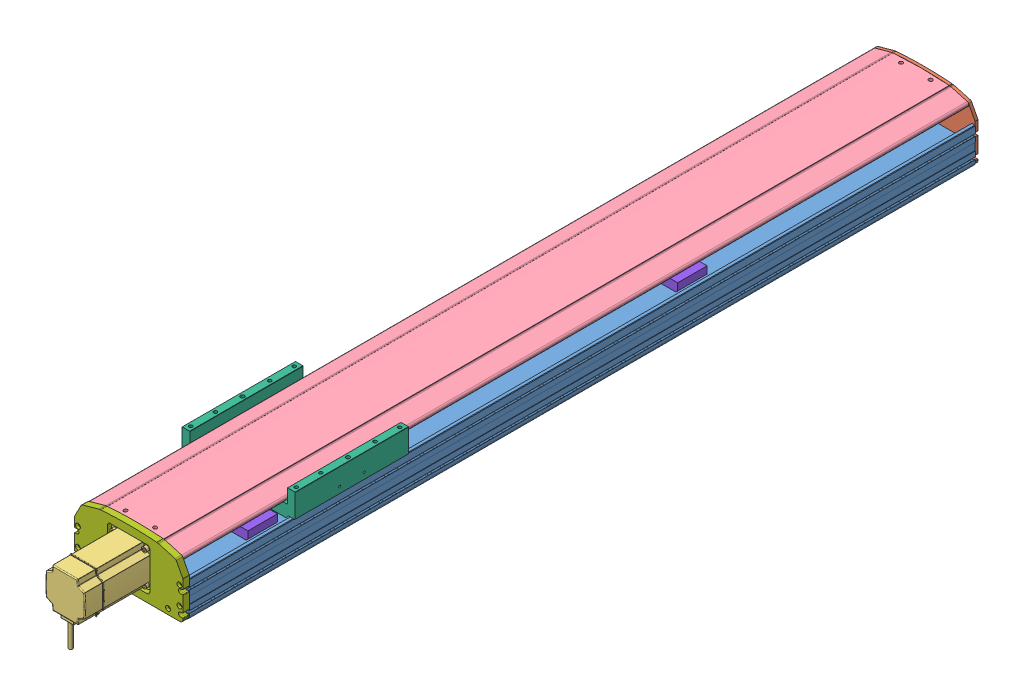
SolidWorks assembly S22M-BC-750W, configuration 默认. Lengths in mm.
Overall size (238.5 161.2 1743).
13 component instances, 10 part files, 44 mates.
Components (placement in the parent):
- S22-BC底座^S22M-BC-750W-1: S22-BC底座^S22M-BC-750W [默认] at origin size (220 72 1595) (virtual)
- S22-GY侧盖^S22M-BC-750W-1: S22-GY侧盖^S22M-BC-750W [默认] at (0 0 -803.5) size (219 117 6) (virtual)
- 750W电机^S22M-BC-750W-1: 750W电机^S22M-BC-750W [默认] at (0 59.8 939.5) x (-1 0 0) z (0 0 -1) size (82 139.7 182) (virtual)
- S22-BC上盖^S22M-BC-750W-1: S22-BC上盖^S22M-BC-750W [默认] at (0 117.9988 0) size (193.4 19.6 1595) (virtual)
- EE-SX672 传感器^S22M-BC-750W-1: EE-SX672 传感器^S22M-BC-750W [默认] at (-116.75 59.85 -536.65) x (-1 0 0) z (0 0 1) size (13.5 27.4 26.1) (virtual)
- EE-SX672 传感器^S22M-BC-750W-2: EE-SX672 传感器^S22M-BC-750W [默认] at (-116.75 59.85 456.3) x (-1 0 0) z (0 0 1) size (13.5 27.4 26.1) (virtual)
- EE-SX672 传感器^S22M-BC-750W-3: EE-SX672 传感器^S22M-BC-750W [默认] at (-116.75 59.85 482.4) x (-1 0 0) z (0 0 1) size (13.5 27.4 26.1) (virtual)
- S22M滑台^S22M-BC-750W-1: S22M滑台^S22M-BC-750W [默认] at (0 0.3 472.5) size (230 80 230) (virtual)
- 复件 电机板S22M-BC-P80^S22M-BC-750W-1: 复件 电机板S22M-BC-P80^S22M-BC-750W [Default] at (0 1 797.5) size (220 118 13) (virtual)
- 复件 滑座S22M^S22M-BC-750W-1: 复件 滑座S22M^S22M-BC-750W [Default] at (0 60.3 607.5) size (198 57 60) (virtual)
- 复件 滑座S22M^S22M-BC-750W-2: 复件 滑座S22M^S22M-BC-750W [Default] at (0 60.3 -264.5) size (198 57 60) (virtual)
- 复件 外置感应片ST22^S22M-BC-750W-1: 复件 外置感应片ST22^S22M-BC-750W [Default] at (-115 64.3 472.5) x (0 0 -1) z (1 0 0) size (70 28 1) (virtual)
- 复件 固定座架S22M-801^S22M-BC-750W-1: 复件 固定座架S22M-801^S22M-BC-750W [默认] at (13.0405 12.9744 692.5) size (164 84 15) (virtual)
Mates (geometry in assembly coordinates):
- 重合1: coincident: plane of S22-BC底座^S22M-BC-750W-1 through (0 0 0) normal (1 0 0); plane of assembly through (0 0 0) normal (1 0 0)
- 重合2: coincident: plane of S22-BC底座^S22M-BC-750W-1 through (0 0 0) normal (0 1 0); plane of assembly through (0 0 0) normal (0 1 0)
- 重合3: coincident: plane of S22-BC底座^S22M-BC-750W-1 through (0 0 0) normal (0 0 1); plane of assembly through (0 0 0) normal (0 0 1)
- 重合4: coincident: plane of S22-BC底座^S22M-BC-750W-1 through (-104.5 14 -797.5) normal (0 0 -1); plane of S22-GY侧盖^S22M-BC-750W-1 through (0 -619.785 -797.5) normal (0 0 1)
- 重合5: coincident: plane of S22-BC底座^S22M-BC-750W-1 through (0 0 0) normal (1 0 0); plane of S22-GY侧盖^S22M-BC-750W-1 through (0 0 -803.5) normal (1 0 0)
- 重合6: coincident: plane of S22-BC底座^S22M-BC-750W-1 through (0 0 0) normal (0 1 0); plane of S22-GY侧盖^S22M-BC-750W-1 through (0 0 -803.5) normal (0 1 0)
- 重合34: coincident: plane of S22-BC底座^S22M-BC-750W-1 through (0 0 0) normal (0 0 1); plane of S22-BC上盖^S22M-BC-750W-1 through (0 117.9988 0) normal (0 0 1)
- 重合36: coincident: plane of S22-BC底座^S22M-BC-750W-1 through (0 0 0) normal (1 0 0); plane of S22-BC上盖^S22M-BC-750W-1 through (0 117.9988 0) normal (1 0 0)
- 重合87: coincident: plane of S22-BC底座^S22M-BC-750W-1 through (-110 16.25 797.5) normal (-1 0 0); plane of EE-SX672 传感器^S22M-BC-750W-1 through (-110 70.95 -530.35) normal (1 0 0)
- 距离23: distance = 260.85 mm: plane of EE-SX672 传感器^S22M-BC-750W-1 through (-123.5 48.75 -536.65) normal (0 0 -1); plane of S22-BC底座^S22M-BC-750W-1 through (-104.5 14 -797.5) normal (0 0 -1)
- 重合91: coincident: plane of EE-SX672 传感器^S22M-BC-750W-2 through (-123.5 70.95 462.6) normal (-1 0 0); plane of EE-SX672 传感器^S22M-BC-750W-3 through (-123.5 70.95 488.7) normal (-1 0 0)
- 重合92: coincident: plane of EE-SX672 传感器^S22M-BC-750W-1 through (-123.5 70.95 -530.35) normal (-1 0 0); plane of EE-SX672 传感器^S22M-BC-750W-2 through (-123.5 70.95 462.6) normal (-1 0 0)
- 重合93: coincident: plane of EE-SX672 传感器^S22M-BC-750W-2 through (-110 48.75 462.6) normal (0 -1 0); plane of EE-SX672 传感器^S22M-BC-750W-3 through (-110 48.75 488.7) normal (0 -1 0)
- 重合94: coincident: plane of EE-SX672 传感器^S22M-BC-750W-1 through (-110 48.75 -530.35) normal (0 -1 0); plane of EE-SX672 传感器^S22M-BC-750W-2 through (-110 48.75 462.6) normal (0 -1 0)
- 距离24: distance = 308.8 mm: plane of EE-SX672 传感器^S22M-BC-750W-3 through (-123.5 48.75 488.7) normal (0 0 1); plane of S22-BC底座^S22M-BC-750W-1 through (-104.5 14 797.5) normal (0 0 1)
- 重合96: coincident: plane of EE-SX672 传感器^S22M-BC-750W-2 through (-113 51.95 472.5) normal (0 0 1); plane of EE-SX672 传感器^S22M-BC-750W-3 through (-113 51.95 472.5) normal (0 0 -1)
- Distance1: distance = 122 mm: plane of S22M滑台^S22M-BC-750W-1 through (99 122.3 587.5) normal (0 1 0); plane of S22-BC底座^S22M-BC-750W-1 through (110 0.3 797.5) normal (0 -1 0)
- Coincident2: coincident: plane of S22-BC底座^S22M-BC-750W-1 through (0 0 0) normal (1 0 0); plane of S22M滑台^S22M-BC-750W-1 through (0 0.3 472.5) normal (1 0 0)
- Distance3: distance = 117.9988 mm: plane of S22-BC上盖^S22M-BC-750W-1 through (0 117.9988 0) normal (0 1 0); plane of S22-BC底座^S22M-BC-750W-1 through (0 0 0) normal (0 1 0)
- 重合97: coincident: plane of S22-BC底座^S22M-BC-750W-1 through (-104.5 14 797.5) normal (0 0 1); plane of 复件 电机板S22M-BC-P80^S22M-BC-750W-1 through (-59.6255 111.4393 797.5) normal (0 0 -1)
- 宽度1: width: plane of 复件 电机板S22M-BC-P80^S22M-BC-750W-1 through (-110 19.5 810.5) normal (-1 0 0); plane of 复件 电机板S22M-BC-P80^S22M-BC-750W-1 through (110 19.5 810.5) normal (1 0 0); plane of S22-BC底座^S22M-BC-750W-1 through (110 57.25 797.5) normal (1 0 0); plane of S22-BC底座^S22M-BC-750W-1 through (-110 57.25 797.5) normal (-1 0 0)
- 同心1: concentric: cylinder of 750W电机^S22M-BC-750W-1 through (0 59.8 735.5) axis (0 0 -1) radius 35; cylinder of 复件 电机板S22M-BC-P80^S22M-BC-750W-1 through (0 59.8 722.5) axis (0 0 1) radius 35
- 重合99: coincident: plane of 750W电机^S22M-BC-750W-1 through (0 59.8 735.5) normal (0 0 -1); plane of 复件 电机板S22M-BC-P80^S22M-BC-750W-1 through (-59.6255 111.4393 735.5) normal (0 0 1)
- 重合100: coincident: plane of 复件 滑座S22M^S22M-BC-750W-1 through (-40.6202 86.3 667.5) normal (0 1 0); plane of 复件 滑座S22M^S22M-BC-750W-2 through (-40.6202 86.3 -204.5) normal (0 1 0)
- 距离25: distance: plane of 复件 滑座S22M^S22M-BC-750W-1 through (40.6202 91.3 607.5) normal (0 0 -1); plane of 复件 滑座S22M^S22M-BC-750W-2 through (40.6202 91.3 -204.5) normal (0 0 1)
- 同心2: concentric: cylinder of S22M滑台^S22M-BC-750W-1 through (0 60.3 587.5) axis (0 0 -1) radius 17.5; cylinder of 复件 滑座S22M^S22M-BC-750W-1 through (0 60.3 667.5) axis (0 0 -1) radius 40
- 同心3: concentric: cylinder of 复件 滑座S22M^S22M-BC-750W-1 through (0 60.3 667.5) axis (0 0 -1) radius 40; cylinder of 复件 滑座S22M^S22M-BC-750W-2 through (0 60.3 -204.5) axis (0 0 -1) radius 40
- 重合102: coincident: plane of 复件 滑座S22M^S22M-BC-750W-1 through (-40.6202 86.3 667.5) normal (0 1 0); plane of 复件 滑座S22M^S22M-BC-750W-2 through (-40.6202 86.3 -204.5) normal (0 1 0)
- 平行1: parallel: plane of S22M滑台^S22M-BC-750W-1 through (99 122.3 587.5) normal (0 1 0); plane of 复件 滑座S22M^S22M-BC-750W-1 through (-40.6202 86.3 667.5) normal (0 1 0)
- 距离26: distance = 0.7 mm: plane of 复件 电机板S22M-BC-P80^S22M-BC-750W-1 through (-104 1 810.5) normal (0 -1 0); plane of S22-BC底座^S22M-BC-750W-1 through (-110 0.3 797.5) normal (0 -1 0)
- 距离27: distance = 20 mm: plane of 复件 滑座S22M^S22M-BC-750W-1 through (40.6202 91.3 607.5) normal (0 0 -1); plane of S22M滑台^S22M-BC-750W-1 through (0 60.3 587.5) normal (0 0 1)
- 宽度3: width: plane of S22-BC底座^S22M-BC-750W-1 through (-110 57.25 797.5) normal (0 -1 0); plane of S22-BC底座^S22M-BC-750W-1 through (-110 52.75 797.5) normal (0 1 0); plane of EE-SX672 传感器^S22M-BC-750W-1 through (-113 58.05 -546.55) normal (0 1 0); plane of EE-SX672 传感器^S22M-BC-750W-1 through (-113 51.95 -546.55) normal (0 -1 0)
- 同心4: concentric: cylinder of S22M滑台^S22M-BC-750W-1 through (-115 87.3 497.5) axis (-1 0 0) radius 2.1; cylinder of 复件 外置感应片ST22^S22M-BC-750W-1 through (-116 87.3 497.5) axis (1 0 0) radius 2.55
- 同心5: concentric: cylinder of S22M滑台^S22M-BC-750W-1 through (-115 87.3 447.5) axis (-1 0 0) radius 2.1; cylinder of 复件 外置感应片ST22^S22M-BC-750W-1 through (-116 87.3 447.5) axis (1 0 0) radius 2.55
- 重合104: coincident: plane of S22M滑台^S22M-BC-750W-1 through (-115 122.3 587.5) normal (-1 0 0); plane of 复件 外置感应片ST22^S22M-BC-750W-1 through (-115 64.3 472.5) normal (1 0 0)
- LimitDistance1: limit distance = 6 mm: line of EE-SX672 传感器^S22M-BC-750W-3 through (-113 52.95 472.5) axis (0 1 0); plane of 复件 外置感应片ST22^S22M-BC-750W-1 through (-116 64.3 466.5) normal (0 0 -1)
- 距离28: distance = 110 mm: cylinder of 750W电机^S22M-BC-750W-1 through (0 59.8 794.5) axis (0 0 -1) radius 9.5; plane of S22-BC底座^S22M-BC-750W-1 through (110 16.25 797.5) normal (1 0 0)
- 距离29: distance = 59.5 mm: cylinder of 750W电机^S22M-BC-750W-1 through (0 59.8 794.5) axis (0 0 -1) radius 9.5; plane of S22-BC底座^S22M-BC-750W-1 through (110 0.3 797.5) normal (0 -1 0)
- 重合105: coincident: line of 750W电机^S22M-BC-750W-1 through (35.1872 97.8901 722.5) axis (-0.998432 0.055975 0); plane of 复件 电机板S22M-BC-P80^S22M-BC-750W-1 through (-59.6255 111.4393 722.5) normal (0 0 -1)
- 平行2: parallel: plane of 750W电机^S22M-BC-750W-1 through (40 99.8 939.5) normal (0 1 0); line of 复件 电机板S22M-BC-P80^S22M-BC-750W-1 through (37 102.8 810.5) axis (-1 0 0)
- 重合107: coincident: plane of 750W电机^S22M-BC-750W-1 through (0 59.8 797.5) normal (0 0 -1); plane of 复件 电机板S22M-BC-P80^S22M-BC-750W-1 through (-59.6255 111.4393 797.5) normal (0 0 -1)
- 同心6: concentric: cylinder of 750W电机^S22M-BC-750W-1 through (0 59.8 794.5) axis (0 0 -1) radius 9.5; cylinder of 复件 固定座架S22M-801^S22M-BC-750W-1 through (0 59.8 797.5) axis (0 0 1) radius 30
- 重合108: coincident: plane of 750W电机^S22M-BC-750W-1 through (0 59.8 797.5) normal (0 0 -1); plane of 复件 固定座架S22M-801^S22M-BC-750W-1 through (-50 34.8 797.5) normal (0 0 1)
- 重合109: coincident: plane of 750W电机^S22M-BC-750W-1 through (40 99.8 939.5) normal (0 1 0); plane of 复件 固定座架S22M-801^S22M-BC-750W-1 through (16.5 99.8 797.5) normal (0 1 0)
